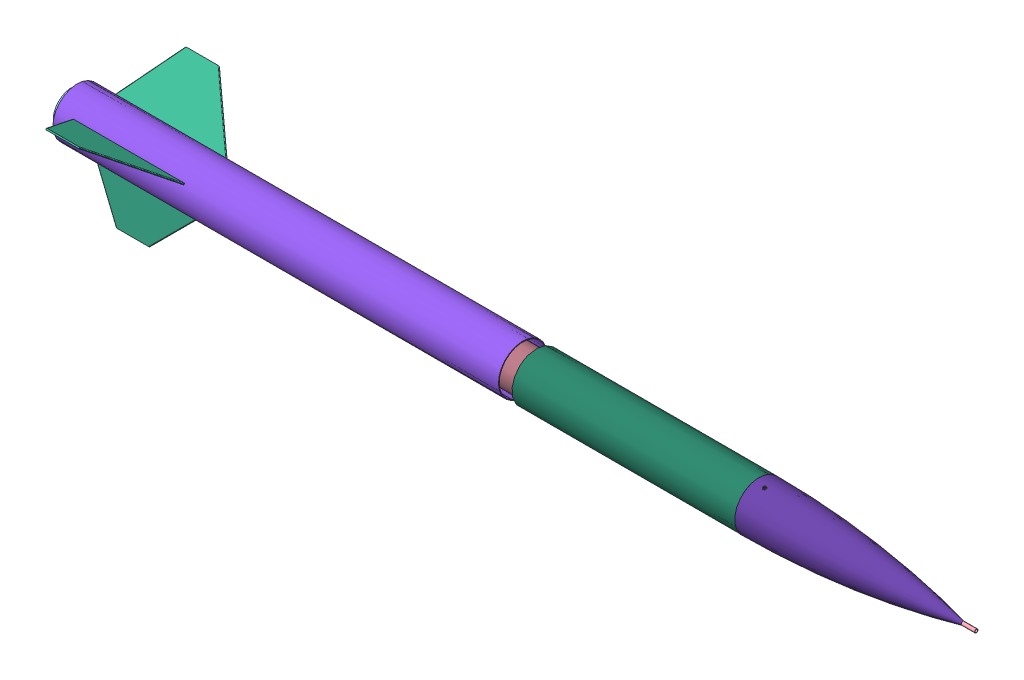
SolidWorks assembly Mudd IV Ultra Assembly, configuration Default. Lengths in mm.
Overall size (1031.4 176.63 181.82).
83 component instances, 29 part files, 4 mates.
Components (placement in the parent):
- Avionics Assembly-1: Avionics Assembly [Default] at (-35.6024 9.1659 12.5597) size (172.47 46.21 46.21)
  - Stack Centering Disk-1: Stack Centering Disk [Default] at (-14.3207 -100.531 114.0982) x (0 0.999058 0.043406) z (1 0 0) size (44.32 44.32 3.81)
  - Stack Centering Disk-2: Stack Centering Disk [Default] at (91.0893 -100.531 114.0982) x (0 -0.999058 -0.043406) z (1 0 0) size (44.32 44.32 3.81)
  - 9V battery-1: 9V battery [Default] at (-35.2105 -110.225 130.4569) x (-1 0 0) z (0 0.043406 -0.999058) size (48.13 26.04 16.78)
  - Stack Assembly-1: Stack Assembly [Default] at (-15.3882 -93.675 112.4807) x (0 -0.999058 -0.043406) z (-1 0 0) size (41.27 23.81 101.6)
    - Big Board (place holder)-1: Big Board (place holder) [Default] at (6.7794 1.9136 -4.8775) size (41.27 14.29 101.6)
    - Small Board (place holder)-1: Small Board (place holder) [Default] at (5.8641 12.2324 -34.9741) x (0 0 1) z (0 1 0) size (101.6 34.92 1.59)
    - Small Board (place holder)-2: Small Board (place holder) [Default] at (7.6946 -9.9926 -76.3808) x (0 0 -1) z (0 1 0) size (101.6 34.92 1.59)
  - 4-40 .5 inch bolt-12: 4-40 .5 inch bolt [Default] at (102.9956 -82.94 118.835) x (0 0.924225 0.381849) z (-1 0 0) size (4.65 4.65 15.54)
  - 4-40 .75 inch bolt-1: 4-40 .75 inch bolt [Default] at (-28.7669 -82.94 118.835) x (0 -0.924225 -0.381849) z (1 0 0) size (4.65 4.65 21.89)
  - 4-40 .75 inch bolt-2: 4-40 .75 inch bolt [Default] at (-28.7669 -118.122 109.3615) x (0 -0.924225 -0.381849) z (1 0 0) size (4.65 4.65 21.89)
  - 4-40 .5 inch bolt-16: 4-40 .5 inch bolt [Default] at (102.9956 -118.4665 117.2915) x (0 0.924225 0.381849) z (-1 0 0) size (4.65 4.65 15.54)
  - 4-40 .5 inch bolt-10: 4-40 .5 inch bolt [Default] at (102.9956 -118.122 109.3615) x (0 0.924225 0.381849) z (-1 0 0) size (4.65 4.65 15.54)
  - 4-40 .75 inch bolt-3: 4-40 .75 inch bolt [Default] at (-28.7669 -118.4665 117.2915) x (0 -0.924225 -0.381849) z (1 0 0) size (4.65 4.65 21.89)
  - 4-40 .75 inch bolt-4: 4-40 .75 inch bolt [Default] at (-28.7669 -82.5955 110.905) x (0 -0.924225 -0.381849) z (1 0 0) size (4.65 4.65 21.89)
  - 4-40 .5 inch bolt-14: 4-40 .5 inch bolt [Default] at (102.9956 -82.5955 110.905) x (0 0.924225 0.381849) z (-1 0 0) size (4.65 4.65 15.54)
  - 4-40 lock nut-1: 4-40 lock nut [Default] at (94.8993 -118.4665 117.2915) x (0 0 -1) z (1 0 0) size (7.33 6.36 2.78)
  - 4-40 lock nut-2: 4-40 lock nut [Default] at (94.8993 -118.122 109.3615) x (0 0 -1) z (1 0 0) size (7.33 6.36 2.78)
  - 4-40 lock nut-3: 4-40 lock nut [Default] at (94.8993 -82.94 118.835) x (0 0 -1) z (1 0 0) size (7.33 6.36 2.78)
  - 4-40 lock nut-4: 4-40 lock nut [Default] at (94.8993 -82.5955 110.905) x (0 0 -1) z (1 0 0) size (7.33 6.36 2.78)
  - 4-40 lock nut-5: 4-40 lock nut [Default] at (-22.2582 -82.5955 110.905) x (0 0 1) z (-1 0 0) size (7.33 6.36 2.78)
  - 4-40 lock nut-6: 4-40 lock nut [Default] at (-22.2582 -82.94 118.835) x (0 0 1) z (-1 0 0) size (7.33 6.36 2.78)
  - 4-40 lock nut-7: 4-40 lock nut [Default] at (-22.2582 -118.122 109.3615) x (0 0 1) z (-1 0 0) size (7.33 6.36 2.78)
  - 4-40 lock nut-8: 4-40 lock nut [Default] at (-22.2582 -118.4665 117.2915) x (0 0 1) z (-1 0 0) size (7.33 6.36 2.78)
  - Battery Holder-1: Battery Holder [Default] at (-64.2444 -100.531 114.0982) x (0 -0.043406 0.999058) z (1 0 0) size (35.34 41.91 48.34)
  - 9V battery-2: 9V battery [Default] at (-35.2105 -109.4979 113.7214) x (-1 0 0) z (0 0.043406 -0.999058) size (48.13 26.04 16.78)
  - Battery Contact and Power Board-1: Battery Contact and Power Board [Default] at (-15.9082 -100.531 114.0982) x (0 0.999058 0.043406) z (1 0 0) size (44.32 44.32 5.4)
  - battery cap-1: battery cap [Default] at (-65.8319 -100.531 114.0982) x (0 0.999058 0.043406) z (1 0 0) size (44.32 44.32 1.59)
  - 4-40 .5 inch bolt-17: 4-40 .5 inch bolt [Default] at (-53.9256 -118.4665 117.2915) x (0 0.291042 0.95671) z (-1 0 0) size (4.65 4.65 15.54)
  - 4-40 .5 inch bolt-18: 4-40 .5 inch bolt [Default] at (-53.9256 -82.4292 110.7673) x (0 0 1) z (-1 0 0) size (4.65 4.65 15.54)
  - 4-40 lock nut-9: 4-40 lock nut [Default] at (-57.8944 -82.5955 110.905) x (0 0 -1) z (1 0 0) size (7.33 6.36 2.78)
  - 4-40 lock nut-10: 4-40 lock nut [Default] at (-57.8944 -118.4665 117.2915) x (0 0 -1) z (1 0 0) size (7.33 6.36 2.78)
  - 4-40 washer-1: 4-40 washer [Default] at (-65.8319 -82.5955 110.905) x (0 0 1) z (-1 0 0) size (5.08 5.08 0.79)
  - 4-40 washer-2: 4-40 washer [Default] at (-65.8319 -118.4665 117.2915) x (0 -0.862439 0.50616) z (-1 0 0) size (5.08 5.08 0.79)
- Parachute Section-1: Parachute Section [Default] at (86.7407 -96.4409 134.6205) x (0 -0.64191 0.76678) z (1 0 0) size (63.96 63.96 325.44)
  - Coupler Bulkplate-1: Coupler Bulkplate [Default] at (-9.3638 1.2192 4.1128) size (41.27 41.27 1.59)
  - Coupler Bulkplate-2: Coupler Bulkplate [Default] at (-9.3638 1.2192 4.1128) x (1 0 0) z (0 0 -1) size (41.27 41.27 1.59)
  - Coupler Tube-1: Coupler Tube [Default] at (-9.3638 1.2192 2.5253) size (44.45 44.45 101.6)
  - Coupler Centering Ring-1: Coupler Centering Ring [Default] at (-9.3638 1.2192 64.4378) size (53.98 53.98 1.59)
  - Coupler Centering Ring-2: Coupler Centering Ring [Default] at (-9.3638 1.2192 102.5378) size (53.98 53.98 1.59)
  - Parachute Section Tube-1: Parachute Section Tube [Default] at (-9.3638 1.2192 64.4378) x (-0.164855 -0.986318 0) z (0 0 1) size (55.56 55.56 254)
  - Connector (pseudo)-1: Connector (pseudo) [Default] at (-24.6038 1.2192 5.7003) x (0.371632 0.92838 0) z (0 0 -1) size (9.53 9.53 12.7)
- Nose Assembly-1: Nose Assembly [Default] at (490.5617 -147.3493 269.9815) x (0 0 1) z (0 1 0) size (68.73 293.88 68.73)
  - Medium Nose Cone-1: Medium Nose Cone [Default] at (-143.3236 -123.4832 55.9843) size (55.63 279.4 55.63)
  - Retention Assembly-1: Retention Assembly [Default] at (-127.7735 -114.4797 56.283) x (0.908442 0 0.41801) z (0 -1 0) size (51.82 51.82 16)
    - Bulkhead3-1: Bulkhead3 [Default] at (-14.2512 6.2286 1.3835) size (50.8 50.8 3.81)
    - Booster Bulkhead-1: Booster Bulkhead [Default] at (-14.2512 6.2286 5.1935) size (51.82 51.82 3.81)
    - Booster Bulkhead Aluminum (without thread)-1: Booster Bulkhead Aluminum (without thread) [Default] at (3.5288 -1.3914 17.1315) x (-1 0 0) z (0 0 -1) size (35.56 15.24 4.06)
    - Booster Bulkhead Aluminum (with thread)-1: Booster Bulkhead Aluminum (with thread) [Default] at (-32.0312 -1.3914 1.1295) size (35.56 15.24 4.06)
    - Booster Bulkhead Aluminum (without thread)-2: Booster Bulkhead Aluminum (without thread) [Default] at (-32.0312 -1.3914 9.0035) size (35.56 15.24 4.06)
  - Pitot Tube Stuff-1: Pitot Tube Stuff [Default] at (-143.3236 -91.7332 55.9843) x (1 0 0) z (0 1 0) size (25.4 40.42 254)
- Booster Assembly-1: Booster Assembly [Default] at (-247.8021 -87.6782 129.052) x (0 0.177242 0.984167) z (-1 0 0) size (157.54 151.1 514.35)
  - MMT and Fin assembly-1: MMT and Fin assembly [Default] at (20.0745 -2.4331 -8.9401) size (157.54 151.1 254)
    - Motor Mount Tube-1: Motor Mount Tube [Default] at (-23.0842 -0.7711 -114.2949) size (41.91 41.91 254)
    - Fin-1: Fin [Default] at (-44.2682 18.3998 44.2916) x (0 0 1) z (-0.650139 -0.759815 0) size (127 71.44 1.59)
    - Fin-2: Fin [Default] at (-29.0946 -28.7025 44.2916) x (0 0 1) z (0.983089 -0.18313 0) size (127 71.44 1.59)
    - Fin-3: Fin [Default] at (4.1104 7.9894 44.2916) x (0 0 1) z (-0.332949 0.942945 0) size (127 71.44 1.59)
    - Minimal Centering Ring-1: Minimal Centering Ring [Default] at (-23.0842 -0.7711 -14.2824) x (0.662098 0.749417 0) z (0 0 1) size (52.35 49.21 1.59)
    - Minimal Centering Ring-2: Minimal Centering Ring [Default] at (-23.0842 -0.7711 114.3051) x (0.662098 0.749417 0) z (0 0 1) size (52.35 49.21 1.59)
  - Airframe Tube-1: Airframe Tube [Default] at (-3.0097 -3.2042 -383.585) x (-0.957333 -0.288987 0) z (0 0 1) size (55.56 55.56 508)
  - Strain Gauge Assembly-2: Strain Gauge Assembly [Default] at (-6.5819 7.0324 -32.5954) x (0.956868 -0.290522 0) z (0 0 1) size (12.7 0.89 50.81)
    - strain gauge part 1-1: strain gauge part 1 [Default] at (6.3921 -8.7572 2.5765) size (12.7 0.89 50.8)
    - strain gauge part 2-1: strain gauge part 2 [Default] at (6.3921 -8.7572 2.5692) x (1 -0.000769 0) z (0 0 1) size (11.18 0.6 50.04)
  - Strain Gauge Assembly-3: Strain Gauge Assembly [Default] at (-6.5819 7.0324 -96.0954) x (0.956868 -0.290522 0) z (0 0 1) size (12.7 0.89 50.81)
    - strain gauge part 1-1: strain gauge part 1 [Default] at (6.3921 -8.7572 2.5765) size (12.7 0.89 50.8)
    - strain gauge part 2-1: strain gauge part 2 [Default] at (6.3921 -8.7572 2.5692) x (1 -0.000769 0) z (0 0 1) size (11.18 0.6 50.04)
  - Strain Gauge Assembly-4: Strain Gauge Assembly [Default] at (-6.5819 7.0324 -159.5954) x (0.956868 -0.290522 0) z (0 0 1) size (12.7 0.89 50.81)
    - strain gauge part 1-1: strain gauge part 1 [Default] at (6.3921 -8.7572 2.5765) size (12.7 0.89 50.8)
    - strain gauge part 2-1: strain gauge part 2 [Default] at (6.3921 -8.7572 2.5692) x (1 -0.000769 0) z (0 0 1) size (11.18 0.6 50.04)
  - Strain Gauge Assembly-5: Strain Gauge Assembly [Default] at (-6.5819 7.0324 -223.0954) x (0.956868 -0.290522 0) z (0 0 1) size (12.7 0.89 50.81)
    - strain gauge part 1-1: strain gauge part 1 [Default] at (6.3921 -8.7572 2.5765) size (12.7 0.89 50.8)
    - strain gauge part 2-1: strain gauge part 2 [Default] at (6.3921 -8.7572 2.5692) x (1 -0.000769 0) z (0 0 1) size (11.18 0.6 50.04)
  - Strain Gauge Assembly-6: Strain Gauge Assembly [Default] at (-6.5819 7.0324 -286.5954) x (0.956868 -0.290522 0) z (0 0 1) size (12.7 0.89 50.81)
    - strain gauge part 1-1: strain gauge part 1 [Default] at (6.3921 -8.7572 2.5765) size (12.7 0.89 50.8)
    - strain gauge part 2-1: strain gauge part 2 [Default] at (6.3921 -8.7572 2.5692) x (1 -0.000769 0) z (0 0 1) size (11.18 0.6 50.04)
  - Strain Gauge Assembly-7: Strain Gauge Assembly [Default] at (-6.5819 7.0324 -350.0954) x (0.956868 -0.290522 0) z (0 0 1) size (12.7 0.89 50.81)
    - strain gauge part 1-1: strain gauge part 1 [Default] at (6.3921 -8.7572 2.5765) size (12.7 0.89 50.8)
    - strain gauge part 2-1: strain gauge part 2 [Default] at (6.3921 -8.7572 2.5692) x (1 -0.000769 0) z (0 0 1) size (11.18 0.6 50.04)
  - Strain Gauge Assembly-10: Strain Gauge Assembly [Default] at (-6.5819 7.0324 30.9046) x (0.956868 -0.290522 0) z (0 0 1) size (12.7 0.89 50.81)
    - strain gauge part 1-1: strain gauge part 1 [Default] at (6.3921 -8.7572 2.5765) size (12.7 0.89 50.8)
    - strain gauge part 2-1: strain gauge part 2 [Default] at (6.3921 -8.7572 2.5692) x (1 -0.000769 0) z (0 0 1) size (11.18 0.6 50.04)
  - Rail Guide-1: Rail Guide [Default] at (-33.7267 0.8963 -231.2594) x (-0.332949 0.942945 0) z (0 0 1) size (6.35 6.35 31.75)
  - Rail Guide-2: Rail Guide [Default] at (-33.7267 0.8963 73.5406) x (-0.332949 0.942945 0) z (0 0 1) size (6.35 6.35 31.75)
Mates (geometry in assembly coordinates):
- Concentric2: concentric anti-aligned: cylinder of Parachute Section-1/Parachute Section Tube-1; cylinder of Nose Assembly-1/Medium Nose Cone-1
- Coincident1: coincident anti-aligned: circle of Parachute Section-1/Parachute Section Tube-1 centre (405.1785 -91.3651 126.658) axis (1 0 0); plane of Nose Assembly-1/Medium Nose Cone-1 through (405.1785 -91.3651 99.6705) normal (-1 0 0)
- Concentric3: concentric aligned: cylinder of Avionics Assembly-1/Stack Centering Disk-1; cylinder of Parachute Section-1/Coupler Tube-1
- Concentric4: concentric anti-aligned: cylinder of Parachute Section-1/Parachute Section Tube-1; cylinder of Booster Assembly-1/Airframe Tube-1
